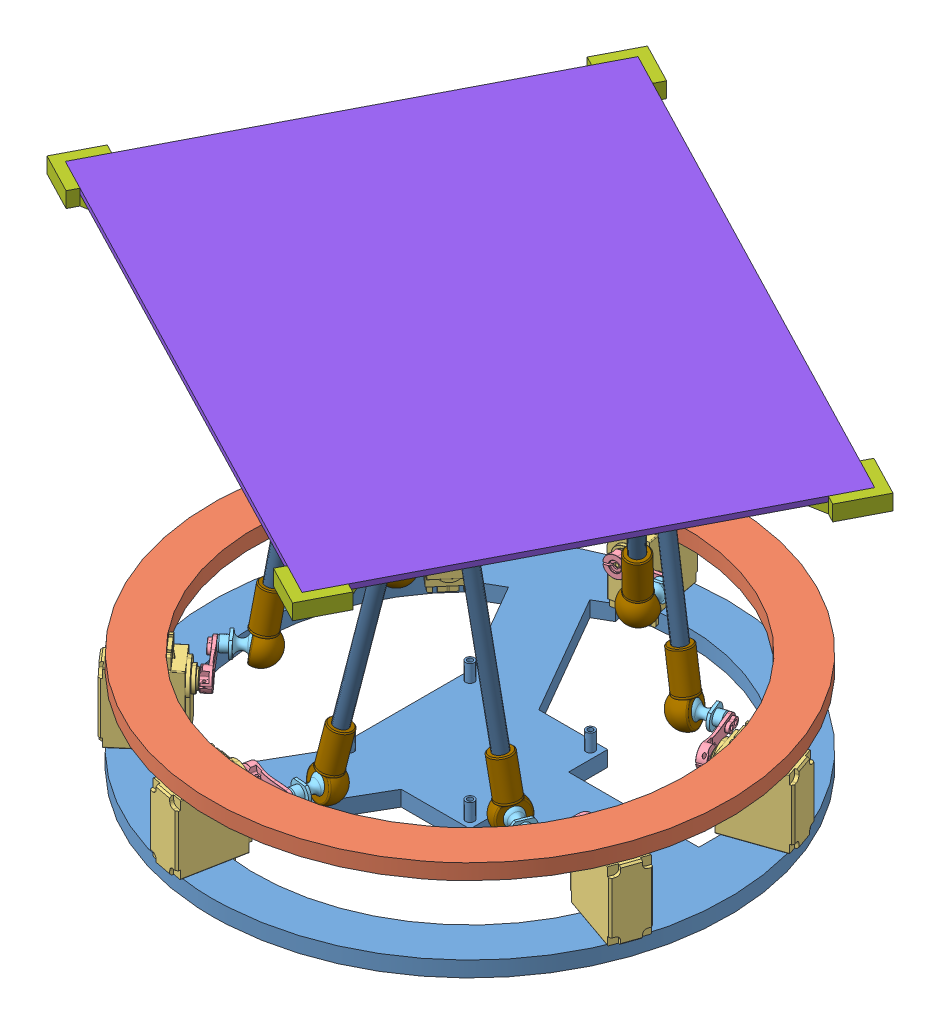
SolidWorks assembly Ensamble_Final, configuration Predeterminado. Lengths in mm.
Overall size (423.22 223.02 423.22).
48 component instances, 10 part files, 87 mates.
Components (placement in the parent):
- Base-1: Base [Predeterminado] at (-59.0283 -42.1725 300) size (300 19 300)
- Base2-1: Base2 [Predeterminado] at (-59.0283 6.8275 300) x (0.754965 0 -0.655765) z (0.655765 0 0.754965) size (300 9 300)
- Servo_Mg995-1: Servo_Mg995 [Predeterminado] at (-174.5959 -13.1725 200.2304) x (0 -1 0) z (0.756949 0 0.653474) size (54 20 45)
- Servo_Mg995-2: Servo_Mg995 [Predeterminado] at (-87.6475 -13.1725 150.0308) x (0 -1 0) z (0.187451 0 0.982274) size (54 20 45)
- Servo_Mg995-3: Servo_Mg995 [Predeterminado] at (85.1585 -13.1725 249.8003) x (0 -1 0) z (-0.9444 0 0.3288) size (54 20 45)
- Servo_Mg995-4: Servo_Mg995 [Predeterminado] at (85.1585 -13.1725 350.1997) x (0 -1 0) z (-0.9444 0 -0.3288) size (54 20 45)
- Servo_Mg995-5: Servo_Mg995 [Predeterminado] at (-87.6475 -13.1725 449.9692) x (0 -1 0) z (0.187451 0 -0.982274) size (54 20 45)
- Servo_Mg995-6: Servo_Mg995 [Predeterminado] at (-174.5959 -13.1725 399.7696) x (0 -1 0) z (0.756949 0 -0.653474) size (54 20 45)
- Servo Mount - Arm Metal Standard-1: Servo Mount - Arm Metal Standard [Défaut] at (40.9606 -3.1725 265.1881) x (-0.031366 -0.995439 -0.090092) z (0.9444 0 -0.3288) size (12.43 33.73 5.41)
- Servo Mount - Arm Metal Standard-2: Servo Mount - Arm Metal Standard [Défaut] at (40.9606 -3.1725 334.8119) x (0.015577 0.998877 -0.04474) z (0.9444 0 0.3288) size (12.43 33.73 5.41)
- Servo Mount - Arm Metal Standard-4: Servo Mount - Arm Metal Standard [Défaut] at (-139.1707 -3.1725 230.813) x (-0.062339 -0.995439 0.07221) z (-0.756949 0 -0.653474) size (12.43 33.73 5.41)
- Servo Mount - Arm Metal Standard-5: Servo Mount - Arm Metal Standard [Défaut] at (-78.8748 -3.1725 403.9988) x (0.093705 -0.995439 0.017882) z (-0.187451 0 0.982274) size (12.43 33.73 5.41)
- Servo Mount - Arm Metal Standard-6: Servo Mount - Arm Metal Standard [Défaut] at (-139.1707 -3.1725 369.187) x (0.030958 0.998877 0.03586) z (-0.756949 0 0.653474) size (12.43 33.73 5.41)
- Servo Mount - Arm Metal Standard-7: Servo Mount - Arm Metal Standard [Défaut] at (-78.8748 -3.1725 196.0012) x (-0.046534 0.998877 0.00888) z (-0.187451 0 -0.982274) size (12.43 33.73 5.41)
- Ball-1: Ball [Default] at (-141.1575 -0.883 260.6595) x (-0.062339 -0.995439 0.07221) z (-0.650494 0.095396 0.753497) size (13 26.5 13)
- Ball-2: Ball [Default] at (-51.9525 -2.0356 209.1883) x (-0.046534 0.998877 0.00888) z (0.981171 0.047374 -0.18724) size (13 26.5 13)
- Ball-3: Ball [Default] at (16.1062 -0.883 248.5443) x (0.031366 0.995439 0.090092) z (0.3273 -0.095396 0.940093) size (13 26.5 13)
- Ball-4: Ball [Default] at (16.079 -2.0356 351.5336) x (0.015577 0.998877 -0.04474) z (-0.328431 0.047374 0.943339) size (13 26.5 13)
- Ball-5: Ball [Default] at (-141.2114 -2.0356 339.278) x (-0.030958 -0.998877 -0.03586) z (0.65274 -0.047374 0.756099) size (13 26.5 13)
- Ball-6: Ball [Default] at (-52.0336 -0.883 390.7962) x (0.093705 -0.995439 0.017882) z (0.977794 0.095396 0.186596) size (13 26.5 13)
- Base_Plataforma-1: Base_Plataforma [Predeterminado] at (6.8043 169.388 179.269) x (0.887764 0 0.460299) z (-0.460299 0 0.887764) size (334 27 259)
  - Efector_Final-1: Efector_Final [Predeterminado] at (-2.8714 -15.5373 137.4833) size (122.44 12 106.04)
  - Base_Pantalla-1: Base_Pantalla [Predeterminado] at (-2.8714 2.4627 137.4833) size (334 27 259)
  - Pantalla-1: Pantalla [Predeterminado] at (-2.8714 8.4627 137.4833) size (322 3 247)
- Ball-7: Ball [Default] at (-34.4021 159.8507 230.7792) x (0 -1 0) z (0.887764 0 0.460299) size (13 26.5 13)
- Ball-8: Ball [Default] at (-16.6468 159.8507 239.9852) x (0 -1 0) z (0.887764 0 0.460299) size (13 26.5 13)
- Ball-9: Ball [Default] at (-132.1934 159.8507 293.304) x (0 1 0) z (0.045251 0 0.998976) size (13 26.5 13)
- Ball-10: Ball [Default] at (-131.2884 159.8507 313.2835) x (0 1 0) z (0.045251 0 0.998976) size (13 26.5 13)
- Ball-11: Ball [Default] at (-28.2447 159.8507 366.7109) x (0.252029 0.954209 -0.16114) z (0.803933 -0.29914 -0.51401) size (13 26.5 13)
- Ball-12: Ball [Default] at (-11.3944 159.8507 355.9374) x (-0.000001 -1 0.000001) z (-0.842513 0.000001 0.538677) size (13 26.5 13)
- RODEND M8 Usable-1: RODEND M8 Usable [Default] at (-132.1934 159.8507 293.304) x (-0.054572 -0.978532 -0.198737) z (0.082491 0.193935 -0.97754) size (39.65 16.42 19.3)
- RODEND M8 Usable-2: RODEND M8 Usable [Default] at (-131.2884 159.8507 313.2835) x (-0.06041 -0.985549 0.158253) z (-0.041627 -0.155917 -0.986893) size (39.65 16.42 19.3)
- RODEND M8 Usable-3: RODEND M8 Usable [Default] at (-11.3944 159.8507 355.9374) x (0.167256 -0.985549 -0.02681) z (-0.852299 -0.158204 0.498555) size (39.65 16.42 19.3)
- RODEND M8 Usable-4: RODEND M8 Usable [Default] at (-28.2447 159.8507 366.7109) x (-0.144825 -0.978532 0.146629) z (-0.79585 0.203254 0.57036) size (39.65 16.42 19.3)
- RODEND M8 Usable-5: RODEND M8 Usable [Default] at (-34.4021 159.8507 230.7792) x (-0.106846 -0.985549 -0.131443) z (0.877534 -0.155627 0.453558) size (39.65 16.42 19.3)
- RODEND M8 Usable-6: RODEND M8 Usable [Default] at (-16.6468 159.8507 239.9852) x (0.199397 -0.978532 0.052107) z (0.783678 0.191163 0.591021) size (39.65 16.42 19.3)
- RODEND M8 Usable-7: RODEND M8 Usable [Default] at (16.1062 -0.883 248.5443) x (-0.199397 0.978532 -0.052107) z (0.360589 0.122714 0.924617) size (39.65 16.42 19.3)
- RODEND M8 Usable-8: RODEND M8 Usable [Default] at (16.079 -2.0356 351.5336) x (-0.167256 0.985549 0.02681) z (-0.333069 -0.082077 0.939323) size (39.65 16.42 19.3)
- RODEND M8 Usable-9: RODEND M8 Usable [Default] at (-51.9525 -2.0356 209.1883) x (0.106846 0.985549 0.131443) z (0.9875 -0.089779 -0.129548) size (39.65 16.42 19.3)
- RODEND M8 Usable-10: RODEND M8 Usable [Default] at (-141.1575 -0.883 260.6595) x (0.054572 0.978532 0.198737) z (0.608058 0.125305 -0.783942) size (39.65 16.42 19.3)
- RODEND M8 Usable-11: RODEND M8 Usable [Default] at (-52.0336 -0.883 390.7962) x (0.144825 0.978532 -0.146629) z (-0.963125 0.105454 -0.247526) size (39.65 16.42 19.3)
- RODEND M8 Usable-12: RODEND M8 Usable [Default] at (-141.2114 -2.0356 339.278) x (0.06041 0.985549 -0.158253) z (-0.611488 -0.08877 -0.786258) size (39.65 16.42 19.3)
- Piernas-2: Piernas [Predeterminado] at (14.741 5.8488 351.7481) x (0.985478 0.166311 0.034271) z (-0.029317 -0.032152 0.999053) size (8 148.26 8)
- Piernas-3: Piernas [Predeterminado] at (14.511 6.9452 248.1274) x (0.979653 0.2003 0.01267) z (-0.022835 0.048521 0.998561) size (8 148.26 8)
- Piernas-4: Piernas [Predeterminado] at (-140.7281 5.8488 338.012) x (0.997584 -0.06506 -0.024361) z (0.034305 0.156399 0.987098) size (8 148.26 8)
- Piernas-5: Piernas [Predeterminado] at (-51.0978 5.8488 210.2399) x (0.9939 -0.109501 0.013122) z (-0.027325 -0.129239 0.991237) size (8 148.26 8)
- Piernas-6: Piernas [Predeterminado] at (-140.7209 6.9452 262.2494) x (0.996842 -0.041891 -0.067467) z (0.057693 -0.201791 0.977728) size (8 148.26 8)
- Piernas-7: Piernas [Predeterminado] at (-50.875 6.9452 389.6232) x (0.989456 -0.143438 0.020046) z (0.001416 0.147986 0.988988) size (8 148.26 8)
Mates (geometry in assembly coordinates):
- Coincidente1: coincident: plane of assembly; plane of assembly; plane of Base-1 through (-59.0283 -33.1725 300) normal (0 1 0); plane of Servo_Mg995-2 through (-77.8247 -33.1725 148.1562) normal (0 -1 0)
- Coincidente2: coincident: plane of assembly; plane of assembly; plane of Base-1 through (-59.0283 -33.1725 300) normal (0 1 0); plane of Servo_Mg995-1 through (-168.0612 -33.1725 192.661) normal (0 -1 0)
- Coincidente3: coincident: plane of assembly; plane of assembly; plane of Base-1 through (-59.0283 -33.1725 300) normal (0 1 0); plane of Servo_Mg995-3 through (88.4465 -33.1725 259.2443) normal (0 -1 0)
- Coincidente4: coincident: plane of assembly; plane of assembly; plane of Base-1 through (-59.0283 -33.1725 300) normal (0 1 0); plane of Servo_Mg995-4 through (81.8705 -33.1725 359.6437) normal (0 -1 0)
- Coincidente5: coincident: plane of assembly; plane of assembly; plane of Base-1 through (-59.0283 -33.1725 300) normal (0 1 0); plane of Servo_Mg995-5 through (-97.4702 -33.1725 448.0947) normal (0 -1 0)
- Coincidente6: coincident: plane of assembly; plane of assembly; plane of Base-1 through (-59.0283 -33.1725 300) normal (0 1 0); plane of Servo_Mg995-6 through (-181.1306 -33.1725 392.2001) normal (0 -1 0)
- Coincidente7: coincident: cylinder of assembly; line of assembly; cylinder of Base-1 through (-59.0283 -33.1725 300) axis (0 -1 0) radius 125; line of Servo_Mg995-6 through (-147.5201 -33.1725 388.2848) axis (0 -1 0)
- Coincidente8: coincident: cylinder of assembly; line of assembly; cylinder of Base-1 through (-59.0283 -33.1725 300) axis (0 -1 0) radius 125; line of Servo_Mg995-6 through (-159.2826 -33.1725 374.6597) axis (0 -1 0)
- Coincidente9: coincident: cylinder of assembly; line of assembly; cylinder of Base-1 through (-59.0283 -33.1725 300) axis (0 -1 0) radius 125; line of Servo_Mg995-5 through (-73.5584 -33.1725 424.1526) axis (0 -1 0)
- Coincidente10: coincident: cylinder of assembly; line of assembly; cylinder of Base-1 through (-59.0283 -33.1725 300) axis (0 -1 0) radius 125; line of Servo_Mg995-5 through (-91.2393 -33.1725 420.7785) axis (0 -1 0)
- Coincidente11: coincident: plane of assembly; line of assembly; plane of Base-1 through (-91.3807 -33.1725 420.7407) normal (0.965926 0 0.258819); line of Servo_Mg995-5 through (-90.8644 -33.1725 418.814) axis (0 -1 0)
- Coincidente12: coincident: plane of assembly; line of assembly; plane of Base-1 through (-143.7564 -33.1725 384.7281) normal (-0.707107 0 -0.707107); line of Servo_Mg995-6 through (-146.0062 -33.1725 386.9779) axis (0 -1 0)
- Coincidente13: coincident: cylinder of assembly; line of assembly; cylinder of Base-1 through (-59.0283 -33.1725 300) axis (0 -1 0) radius 125; line of Servo_Mg995-1 through (-159.2826 -33.1725 225.3403) axis (0 -1 0)
- Coincidente14: coincident: cylinder of assembly; line of assembly; cylinder of Base-1 through (-59.0283 -33.1725 300) axis (0 -1 0) radius 125; line of Servo_Mg995-1 through (-147.5201 -33.1725 211.7152) axis (0 -1 0)
- Coincidente15: coincident: plane of assembly; line of assembly; plane of Base-1 through (-147.4166 -33.1725 211.6117) normal (-0.707107 0 0.707107); line of Servo_Mg995-1 through (-146.0062 -33.1725 213.0221) axis (0 -1 0)
- Coincidente17: coincident: cylinder of assembly; line of assembly; cylinder of Base-1 through (-59.0283 -33.1725 300) axis (0 -1 0) radius 125; line of Servo_Mg995-2 through (-73.5584 -33.1725 175.8474) axis (0 -1 0)
- Coincidente18: coincident: cylinder of assembly; line of assembly; plane of ?; cylinder of Base-1 through (-59.0283 -33.1725 300) axis (0 -1 0) radius 125; line of Servo_Mg995-2 through (-91.2393 -33.1725 179.2215) axis (0 -1 0)
- Coincidente19: coincident: plane of assembly; line of assembly; plane of Base-1 through (-90.0409 -33.1725 184.2593) normal (0.965926 0 -0.258819); line of Servo_Mg995-2 through (-90.8644 -33.1725 181.186) axis (0 -1 0)
- Coincidente20: coincident: cylinder of assembly; line of assembly; cylinder of Base-1 through (-59.0283 -33.1725 300) axis (0 -1 0) radius 125; line of Servo_Mg995-4 through (55.7561 -33.1725 349.4929) axis (0 -1 0)
- Coincidente21: coincident: cylinder of assembly; line of assembly; cylinder of Base-1 through (-59.0283 -33.1725 300) axis (0 -1 0) radius 125; line of Servo_Mg995-4 through (61.6745 -33.1725 332.4937) axis (0 -1 0)
- Coincidente22: coincident: plane of assembly; line of assembly; plane of Base-1 through (56.7124 -33.1725 331.0126) normal (-0.258819 0 0.965926); line of Servo_Mg995-4 through (59.7857 -33.1725 331.8361) axis (0 -1 0)
- Coincidente23: coincident: cylinder of assembly; line of assembly; cylinder of Base-1 through (-59.0283 -33.1725 300) axis (0 -1 0) radius 125; line of Servo_Mg995-3 through (55.7561 -33.1725 250.5071) axis (0 -1 0)
- Coincidente24: coincident: cylinder of assembly; line of assembly; cylinder of Base-1 through (-59.0283 -33.1725 300) axis (0 -1 0) radius 125; line of Servo_Mg995-3 through (61.6745 -33.1725 267.5063) axis (0 -1 0)
- Coincidente25: coincident: plane of assembly; line of assembly; plane of Base-1 through (61.7124 -33.1725 267.6476) normal (-0.258819 0 -0.965926); line of Servo_Mg995-3 through (59.7857 -33.1725 268.1639) axis (0 -1 0)
- Concéntrica2: concentric: cylinder of assembly; cylinder of assembly; cylinder of Base-1 through (-59.0283 -33.1725 300) axis (0 -1 0) radius 150; cylinder of Base2-1 through (-59.0283 15.8275 300) axis (0 -1 0) radius 150
- Coincidente26: coincident: plane of assembly; plane of assembly; plane of Base2-1 through (-59.0283 6.8275 300) normal (0 -1 0); plane of Servo_Mg995-4 through (88.4465 6.8275 340.7557) normal (0 1 0)
- Coincidente34: coincident: circle of assembly; circle of assembly; circle of Servo_Mg995-3; circle of Servo Mount - Arm Metal Standard-1
- Coincidente35: coincident: circle of assembly; circle of assembly; circle of Servo_Mg995-4; circle of Servo Mount - Arm Metal Standard-2
- Coincidente36: coincident: circle of assembly; circle of assembly; circle of Servo_Mg995-5; circle of Servo Mount - Arm Metal Standard-5
- Coincidente37: coincident: circle of assembly; circle of assembly; circle of Servo_Mg995-6; circle of Servo Mount - Arm Metal Standard-6
- Coincidente38: coincident: circle of assembly; circle of assembly; circle of Servo_Mg995-1; circle of Servo Mount - Arm Metal Standard-4
- Coincidente39: coincident: circle of assembly; circle of assembly; circle of Servo_Mg995-2; circle of Servo Mount - Arm Metal Standard-7
- Ángulo límite1: limit planar angle = 1.523405 rad: line of assembly; line of assembly; line of Servo Mount - Arm Metal Standard-6 through (-140.8662 -3.605 368.7532) axis (-0.65274 0.047374 -0.756099); line of Servo_Mg995-6 through (-152.2142 6.8275 379.7869) axis (0 1 0)
- Ángulo límite2: limit planar angle = 1.475255 rad: line of assembly; line of assembly; line of Servo Mount - Arm Metal Standard-5 through (-77.6326 -3.5353 405.2539) axis (0.977794 0.095396 0.186596); line of Servo_Mg995-5 through (-81.5328 6.8275 420.5948) axis (0 1 0)
- Ángulo límite3: limit planar angle = 1.523405 rad: line of assembly; line of assembly; line of Servo Mount - Arm Metal Standard-2 through (41.4327 -3.605 336.4971) axis (-0.328431 0.047374 0.943339); line of Servo_Mg995-4 through (56.6621 6.8275 340.8079) axis (0 1 0)
- Ángulo límite4: limit planar angle = 1.475255 rad: line of assembly; line of assembly; line of Servo Mount - Arm Metal Standard-1 through (41.4264 -3.5353 263.4848) axis (-0.3273 0.095396 -0.940093); line of Servo_Mg995-3 through (56.6621 6.8275 259.1921) axis (0 1 0)
- Ángulo límite5: limit planar angle = 1.523405 rad: line of assembly; line of assembly; line of Servo Mount - Arm Metal Standard-7 through (-77.6514 -3.605 194.7497) axis (0.981171 0.047374 -0.18724); line of Servo_Mg995-2 through (-81.5328 6.8275 179.4052) axis (0 1 0)
- Ángulo límite6: limit planar angle = 1.475255 rad: line of assembly; line of assembly; line of Servo Mount - Arm Metal Standard-4 through (-140.8787 -3.5353 231.2613) axis (-0.650494 0.095396 0.753497); line of Servo_Mg995-1 through (-152.2142 6.8275 220.2131) axis (0 1 0)
- Coincidente43: coincident: circle of assembly; circle of assembly; circle of Servo Mount - Arm Metal Standard-4; circle of Ball-1
- Coincidente44: coincident: circle of assembly; circle of assembly; circle of Servo Mount - Arm Metal Standard-7; circle of Ball-2
- Coincidente45: coincident: circle of assembly; circle of assembly; circle of Servo Mount - Arm Metal Standard-1; circle of Ball-3
- Coincidente46: coincident: circle of assembly; circle of assembly; circle of Servo Mount - Arm Metal Standard-2; circle of Ball-4
- Coincidente47: coincident: circle of assembly; circle of assembly; circle of Servo Mount - Arm Metal Standard-5; circle of Ball-6
- Coincidente48: coincident: circle of assembly; circle of assembly; circle of Servo Mount - Arm Metal Standard-6; circle of Ball-5
- Concéntrica6: concentric: sphere of assembly; sphere of assembly; sphere of Ball-11; sphere of RODEND M8 Usable-4
- Concéntrica7: concentric: sphere of assembly; sphere of assembly; sphere of Ball-12; sphere of RODEND M8 Usable-3
- Concéntrica8: concentric: sphere of assembly; sphere of assembly; sphere of Ball-10; sphere of RODEND M8 Usable-2
- Concéntrica9: concentric: sphere of assembly; sphere of assembly; sphere of Ball-9; sphere of RODEND M8 Usable-1
- Concéntrica10: concentric: sphere of assembly; sphere of assembly; sphere of Ball-8; sphere of RODEND M8 Usable-6
- Concéntrica11: concentric: sphere of assembly; sphere of assembly; sphere of Ball-7; sphere of RODEND M8 Usable-5
- Concéntrica12: concentric: sphere of assembly; sphere of assembly; sphere of Ball-5; sphere of RODEND M8 Usable-12
- Concéntrica13: concentric: sphere of assembly; sphere of assembly; sphere of Ball-6; sphere of RODEND M8 Usable-11
- Concéntrica14: concentric: sphere of assembly; sphere of assembly; sphere of Ball-3; sphere of RODEND M8 Usable-7
- Concéntrica15: concentric: sphere of assembly; sphere of assembly; sphere of Ball-4; sphere of RODEND M8 Usable-8
- Concéntrica16: concentric: sphere of assembly; sphere of assembly; sphere of Ball-1; sphere of RODEND M8 Usable-10
- Concéntrica17: concentric: sphere of assembly; sphere of assembly; sphere of Ball-2; sphere of RODEND M8 Usable-9
- CentroDePerfil1: profile center = 0 mm: circle of RODEND M8 Usable-9; circle of Piernas-5
- CentroDePerfil2: profile center = 0 mm: circle of Piernas-6; circle of RODEND M8 Usable-10
- CentroDePerfil3: profile center = 0 mm: circle of Piernas-4; circle of RODEND M8 Usable-12
- CentroDePerfil4: profile center = 0 mm: circle of RODEND M8 Usable-11; circle of Piernas-7
- CentroDePerfil5: profile center = 0 mm: circle of Piernas-3; circle of RODEND M8 Usable-7
- CentroDePerfil6: profile center = 0 mm: circle of Piernas-2; circle of RODEND M8 Usable-8
- CentroDePerfil7: profile center = 0 mm: circle of Piernas-2; circle of RODEND M8 Usable-3
- CentroDePerfil8: profile center = 0 mm: circle of RODEND M8 Usable-4; circle of Piernas-7
- CentroDePerfil9: profile center = 0 mm: circle of RODEND M8 Usable-2; circle of Piernas-4
- CentroDePerfil10: profile center = 0 mm: circle of RODEND M8 Usable-1; circle of Piernas-6
- CentroDePerfil12: profile center = 0 mm: circle of RODEND M8 Usable-6; circle of Piernas-3
- CentroDePerfil13: profile center = 0 mm: circle of RODEND M8 Usable-5; circle of Piernas-5
- Paralelo13: parallel: plane of assembly; plane of assembly; plane of Servo Mount - Arm Metal Standard-6 through (-150.3474 1.283 359.3011) normal (0.030958 0.998877 0.03586); plane of Ball-5 through (-144.4011 2.7621 347.8255) normal (0.030958 0.998877 0.03586)
- Paralelo14: parallel: plane of assembly; plane of assembly; plane of Servo Mount - Arm Metal Standard-5 through (-56.134 2.8499 410.3746) normal (-0.093705 0.995439 -0.017882); plane of Ball-6 through (-49.9406 4.4904 399.34) normal (-0.093705 0.995439 -0.017882)
- Paralelo15: parallel: plane of assembly; plane of assembly; plane of Servo Mount - Arm Metal Standard-2 through (37.9875 1.283 349.4341) normal (0.015577 0.998877 -0.04474); plane of Ball-4 through (25.0762 2.7621 350.0223) normal (0.015577 0.998877 -0.04474)
- Paralelo16: parallel: plane of assembly; plane of assembly; plane of Servo Mount - Arm Metal Standard-1 through (35.1118 2.8499 242.3062) normal (0.031366 0.995439 0.090092); plane of Ball-3 through (24.8639 -6.2564 249.3679) normal (-0.031366 -0.995439 -0.090092)
- Paralelo17: parallel: plane of assembly; plane of assembly; plane of Servo Mount - Arm Metal Standard-7 through (-64.725 1.283 191.2648) normal (-0.046534 0.998877 0.00888); plane of Ball-2 through (-57.7599 2.7621 202.1522) normal (-0.046534 0.998877 0.00888)
- Paralelo18: parallel: plane of assembly; plane of assembly; plane of Servo Mount - Arm Metal Standard-4 through (-156.0627 2.8499 247.3192) normal (0.062339 0.995439 -0.07221); plane of Ball-1 through (-149.6031 4.4904 258.2002) normal (0.062339 0.995439 -0.07221)
- Ángulo límite18: limit planar angle = 0.179875 rad: plane of assembly; plane of assembly; plane of RODEND M8 Usable-10 through (-150.6725 -10.0311 264.1266) normal (-0.792015 0.163625 -0.588166); plane of Servo Mount - Arm Metal Standard-4 through (-154.7825 -0.883 248.897) normal (0.756949 0 0.653474)
- Ángulo límite19: limit planar angle = 0.160661 rad: plane of assembly; plane of assembly; plane of RODEND M8 Usable-9 through (-62.8837 -9.2497 205.3529) normal (-0.115875 0.143642 -0.982822); plane of Servo Mount - Arm Metal Standard-7 through (-55.3267 -2.0356 191.5074) normal (0.187451 0 0.982274)
- Ángulo límite20: limit planar angle = 0.175937 rad: plane of assembly; plane of assembly; plane of RODEND M8 Usable-7 through (18.0222 -9.9983 238.5701) normal (0.911162 0.165576 -0.377317); plane of Servo Mount - Arm Metal Standard-1 through (33.1054 -0.883 242.6259) normal (-0.9444 0 0.3288)
- Ángulo límite21: limit planar angle = 0.14981 rad: plane of assembly; plane of assembly; plane of RODEND M8 Usable-8 through (24.4738 -9.3058 343.6016) normal (0.927949 0.148178 0.341984); plane of Servo Mount - Arm Metal Standard-2 through (33.0782 -2.0356 357.452) normal (-0.9444 0 -0.3288)
- Ángulo límite22: limit planar angle = 0.183289 rad: plane of assembly; plane of assembly; plane of Servo Mount - Arm Metal Standard-5 through (-55.4077 -0.883 408.4771) normal (0.187451 0 -0.982274); plane of RODEND M8 Usable-11 through (-44.9183 -9.7858 398.3034) normal (-0.226749 0.17707 0.957722)
- Ángulo límite23: limit planar angle = 0.158259 rad: plane of assembly; plane of assembly; plane of Servo Mount - Arm Metal Standard-6 through (-154.8365 -2.0356 351.0406) normal (0.756949 0 -0.653474); plane of RODEND M8 Usable-12 through (-138.9968 -9.2569 350.6444) normal (-0.788944 0.144268 0.597289)
- Concéntrica21: concentric: cylinder of assembly; cylinder of assembly; cylinder of Base-1 through (-59.0283 -33.1725 300) axis (0 -1 0) radius 125; cylinder of Base_Plataforma-1/Efector_Final-1 through (-59.0283 165.8507 300) axis (0 -1 0) radius 28.75
- Coincidente76: coincident: circle of assembly; circle of assembly; circle of Base_Plataforma-1/Efector_Final-1; circle of Ball-12
- Coincidente79: coincident: circle of assembly; circle of assembly; circle of Base_Plataforma-1/Efector_Final-1; circle of Ball-11
- Coincidente80: coincident: circle of assembly; circle of assembly; circle of Base_Plataforma-1/Efector_Final-1; circle of Ball-10
- Coincidente81: coincident: circle of assembly; circle of assembly; circle of Base_Plataforma-1/Efector_Final-1; circle of Ball-9
- Coincidente82: coincident: circle of assembly; circle of assembly; circle of Base_Plataforma-1/Efector_Final-1; circle of Ball-7
- Coincidente83: coincident: circle of assembly; circle of assembly; circle of Base_Plataforma-1/Efector_Final-1; circle of Ball-8
